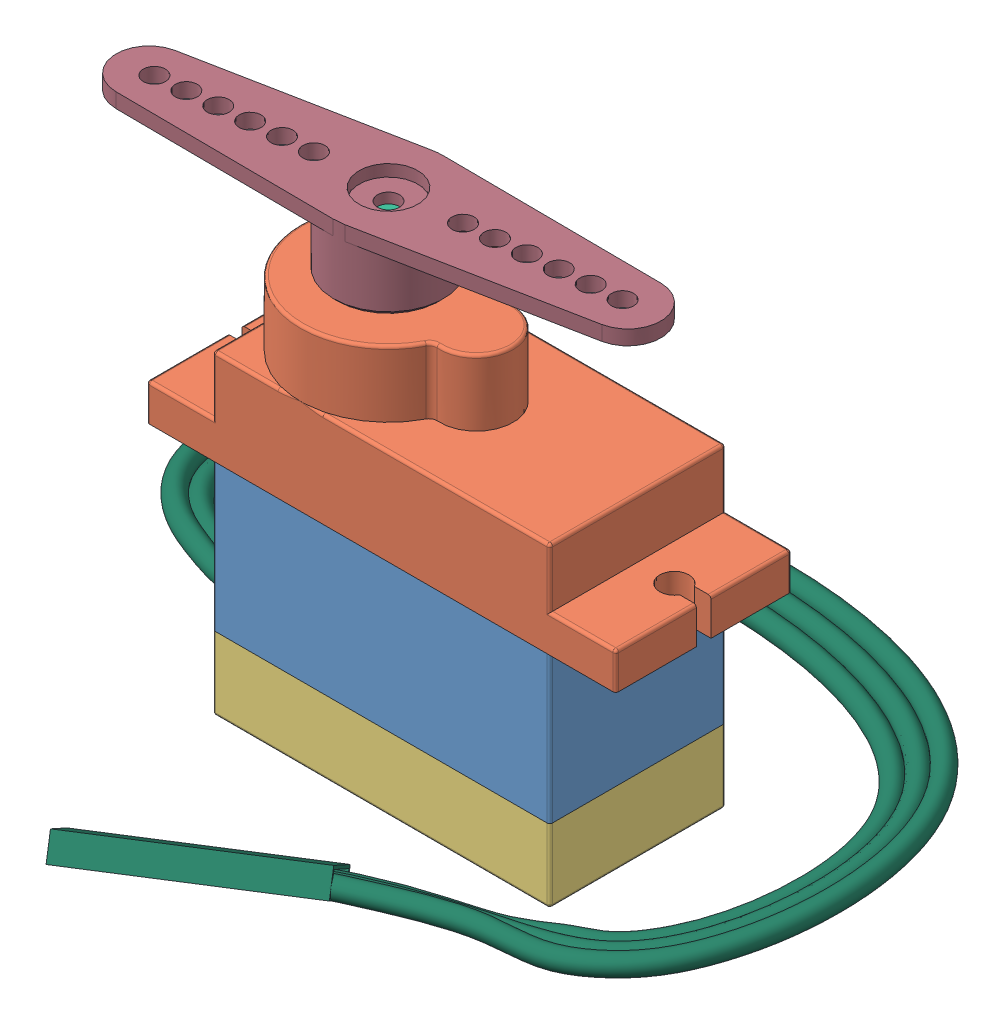
SolidWorks assembly TowPro-SG90-9g, configuration Défaut. Lengths in mm.
Overall size (48.83 32.86 44.12).
19 component instances, 15 part files, 51 mates.
Components (placement in the parent):
- Piece2-1: Piece2 [Défaut] at origin size (23 11 12)
- Piece3-1: Piece3 [Défaut] at (0 -1 0) size (32 11 12)
- Piece1-1: Piece1 [Défaut] at origin size (23 5 12)
- Gear02-1: Gear02 [Défaut] at (12.13 15.3 6) x (0 1 0) z (0.72317 0 0.69067) size (2.67 10.24 10.25)
- Gear01-1: Gear01 [Défaut] at (18.225 15 6) x (0 1 0) z (-0.948587 0 -0.316515) size (2 2.87 3)
- Gear04-1: Gear04 [Défaut] at (6 25 6) x (0 -1 0) z (0.996577 0 -0.082668) size (6.6 10.24 10.25)
- Gear02-2: Gear02 [Défaut] at (6 16.7 6) x (0 1 0) z (-0.746148 0 -0.66578) size (2.67 10.24 10.25)
- Gear03-1: Gear03 [Défaut] at (12.13 18.05 6) x (0 1 0) z (-0.892089 0 0.45186) size (6.94 10.24 10.25)
- AXE01-1: AXE01 [Défaut] at (12.13 25.5 6) x (1 0 0) z (0 -1 0) size (0.8 0.8 11)
- Pot1-1: Pot1 [Défaut] at (6 12 6) x (0 0 -1) z (0 1 0) size (10 10.16 4.72)
- Pot2-1: Pot2 [Défaut] at (6 12.0113 6) x (0.156026 0 -0.987753) z (0 1 0) size (9.16 8.4 14.53)
- Motor1-1: Motor1 [Default] at (18.225 9.2 6) x (0 0 -1) z (0 1 0) size (10.1 8.78 13.8)
- Motor2-1: Motor2 [Default] at (18.225 9.15 6) x (-0.963319 0 0.26836) z (0 1 0) size (6.5 6.42 15.75)
- A2-1: A2 [Default] at (6 31.1332 6) x (0.092609 0 0.995703) z (0 -1 0) size (7.5 34.5 5)
- Vis-1: Vis [Défaut] at (21.75 0 10.75) x (-0.99793 0 -0.064304) z (0 1 0) size (2 2 19.91)
- Vis-2: Vis [Défaut] at (1.25 0 10.75) x (1 0 0) z (0 1 0) size (2 2 19.91)
- Vis-3: Vis [Défaut] at (21.75 0 1.25) x (1 0 0) z (0 1 0) size (2 2 19.91)
- Vis-4: Vis [Défaut] at (1.25 0 1.25) x (1 0 0) z (0 1 0) size (2 2 19.91)
- W3.0-1: W3.0 [Défaut] at (0 -0.0833 0) size (48.83 7.25 44.12)
Mates (geometry in assembly coordinates):
- Coïncidente2: coincident aligned: plane of Piece2-1 through (0 0 12) normal (-1 0 0); plane of Piece3-1 through (0 17.5 12) normal (-1 0 0)
- Coïncidente3: coincident anti-aligned: plane of Piece2-1 through (-7.4113 15 12) normal (0 1 0); plane of Piece3-1 through (0 15 12) normal (0 -1 0)
- Coïncidente5: coincident anti-aligned: plane of Piece2-1 through (-7.4113 5 12) normal (0 -1 0); plane of Piece1-1 through (-7.4113 5 12) normal (0 1 0)
- Coïncidente6: coincident aligned: plane of Piece2-1 through (0 0 12) normal (-1 0 0); plane of Piece1-1 through (0 0 12) normal (-1 0 0)
- Coïncidente10: coincident anti-aligned: plane of Piece2-1 through (12.13 15.3 6) normal (0 1 0); plane of Gear02-1 through (12.13 15.3 6) normal (0 -1 0)
- Coaxiale3: concentric anti-aligned: cylinder of Piece2-1 through (12.13 14.5 6) axis (0 1 0) radius 0.4; cylinder of Gear02-1 through (12.13 15.3 6) axis (0 -1 0) radius 0.4
- Coïncidente11: coincident anti-aligned: plane of Piece2-1 through (-7.4113 15 12) normal (0 1 0); plane of Gear01-1 through (18.8118 15 5.9758) normal (0 -1 0)
- Coaxiale4: concentric anti-aligned: cylinder of Piece2-1 through (18.225 5 6) axis (0 1 0) radius 1.55; cylinder of Gear01-1 through (18.225 17 6) axis (0 -1 0) radius 0.5
- Contr.Engrenages1: gear = 39 : 10 mm: circle of Gear01-1; circle of Gear02-1
- Coïncidente12: coincident anti-aligned: plane of Piece3-1 through (6 24 6) normal (0 -1 0); plane of Gear04-1 through (6 24 6) normal (0 1 0)
- Coaxiale5: concentric anti-aligned: cylinder of Piece3-1 through (6 5.2 6) axis (0 1 0) radius 2.5; cylinder of Gear04-1 through (6 28.0001 6) axis (0 -1 0) radius 2.5
- Coaxiale6: concentric aligned: cylinder of Gear04-1 through (6 28.0001 6) axis (0 -1 0) radius 2.5; cylinder of Gear02-2 through (6 16.7 6) axis (0 -1 0) radius 0.4
- Distance1: distance = 0.4 mm anti-aligned: plane of Gear02-2 through (6 16.7 6) normal (0 -1 0); plane of Gear02-1 through (8.5903 16.3 9.7062) normal (0 1 0)
- Contr.Engrenages2: gear = 39 : 10 mm: circle of Gear02-1; circle of Gear02-2
- Coaxiale7: concentric aligned: cylinder of Gear02-1 through (12.13 15.3 6) axis (0 -1 0) radius 0.4; cylinder of Gear03-1 through (12.13 18.05 6) axis (0 -1 0) radius 0.4
- Distance2: distance = 0.35 mm anti-aligned: plane of Gear03-1 through (12.13 18.05 6) normal (0 -1 0); plane of Gear02-2 through (9.4121 17.7 2.176) normal (0 1 0)
- Contr.Engrenages3: gear = 10 : 39 mm: circle of Gear03-1; circle of Gear02-2
- Contr.Engrenages4: gear = 39 : 10 mm: circle of Gear03-1; circle of Gear04-1
- Coaxiale8: concentric anti-aligned: cylinder of Piece3-1 through (12.13 25.5 6) axis (0 -1 0) radius 0.4; cylinder of AXE01-1 through (12.13 14.5 6) axis (0 1 0) radius 0.4
- Coïncidente13: coincident anti-aligned: plane of Piece3-1 through (12.13 25.5 6) normal (0 -1 0); plane of AXE01-1 through (12.13 25.5 6) normal (0 1 0)
- Coaxiale9: concentric anti-aligned: cylinder of Piece2-1 through (6 5 6) axis (0 1 0) radius 5; cylinder of Pot1-1 through (6 15 6) axis (0 -1 0) radius 5
- Coïncidente14: coincident aligned: plane of Piece2-1 through (-7.4113 15 12) normal (0 1 0); plane of Pot1-1 through (6 15 6) normal (0 1 0)
- Coaxiale10: concentric anti-aligned: cylinder of Pot1-1 through (6 15 6) axis (0 -1 0) radius 4.75; cylinder of Pot2-1 through (6 19.6836 6) axis (0 1 0) radius 0.5
- Coïncidente15: coincident anti-aligned: plane of Pot1-1 through (6.8085 11.35 5) normal (0 -1 0); plane of Pot2-1 through (6.4939 11.35 6.078) normal (0 1 0)
- Verrouiller1: lock: unknown of Gear04-1; unknown of Pot2-1
- Parallèle1: parallel aligned: plane of Piece2-1 through (1 4 1) normal (1 0 0); plane of Pot1-1 through (7 11 10.899) normal (1 0 0)
- Coïncidente16: coincident anti-aligned: plane of Piece2-1 through (22 4 1) normal (-1 0 0); plane of Motor1-1 through (22 4.5 9.3166) normal (1 0 0)
- Coaxiale11: concentric anti-aligned: cylinder of Piece2-1 through (18.225 5 6) axis (0 1 0) radius 1.55; cylinder of Motor1-1 through (18.225 14.85 6) axis (0 -1 0) radius 1.5375
- Coïncidente17: coincident anti-aligned: plane of Piece2-1 through (0 14 0) normal (0 -1 0); plane of Motor1-1 through (18.225 14 6) normal (0 1 0)
- Coaxiale12: concentric anti-aligned: cylinder of Motor1-1 through (18.225 13.7 6) axis (0 1 0) radius 0.55; cylinder of Motor2-1 through (18.225 18.65 6) axis (0 -1 0) radius 0.5
- Coïncidente18: coincident anti-aligned: plane of Motor1-1 through (18.225 2.95 5.5) normal (0 1 0); plane of Motor2-1 through (18.225 2.95 6) normal (0 -1 0)
- Verrouiller2: lock: unknown of Gear01-1; unknown of Motor2-1
- Coaxiale13: concentric anti-aligned: cylinder of Gear04-1 through (6 28.0001 6) axis (0 -1 0) radius 2.5; cylinder of A2-1 through (6 30.1332 6) axis (0 1 0) radius 3.75
- Verrouiller3: lock: unknown of Gear04-1; unknown of A2-1
- Coïncidente19: coincident aligned: plane of Piece2-1 through (0 0 0) normal (0 0 -1); plane of Piece3-1 through (0 -1 0) normal (0 0 -1)
- Coïncidente20: coincident aligned: plane of Piece2-1 through (0 0 0) normal (0 0 -1); plane of Piece1-1 through (0 0 0) normal (0 0 -1)
- Coaxiale14: concentric aligned: cylinder of Piece1-1 through (21.75 3.5 10.75) axis (0 -1 0) radius 0.6; cylinder of Vis-1 through (21.75 19.9 10.75) axis (0 -1 0) radius 0.5
- Coïncidente21: coincident anti-aligned: plane of Piece1-1 through (21.75 0.9 10.75) normal (0 -1 0); plane of Vis-1 through (21.75 0.9 10.75) normal (0 1 0)
- Coaxiale15: concentric aligned: cylinder of Piece1-1 through (1.25 3.5 1.25) axis (0 -1 0) radius 0.6; cylinder of Vis-4 through (1.25 19.9 1.25) axis (0 -1 0) radius 0.5
- Coaxiale16: concentric aligned: cylinder of Piece1-1 through (1.25 3.5 10.75) axis (0 -1 0) radius 0.6; cylinder of Vis-2 through (1.25 19.9 10.75) axis (0 -1 0) radius 0.5
- Coaxiale17: concentric aligned: cylinder of Piece1-1 through (21.75 3.5 1.25) axis (0 -1 0) radius 0.6; cylinder of Vis-3 through (21.75 19.9 1.25) axis (0 -1 0) radius 0.5
- Coïncidente22: coincident anti-aligned: plane of Piece1-1 through (21.75 0.9 1.25) normal (0 -1 0); plane of Vis-3 through (21.75 0.9 1.25) normal (0 1 0)
- Coïncidente23: coincident anti-aligned: plane of Piece1-1 through (1.25 0.9 10.75) normal (0 -1 0); plane of Vis-2 through (1.25 0.9 10.75) normal (0 1 0)
- Coïncidente24: coincident anti-aligned: plane of Piece1-1 through (1.25 0.9 1.25) normal (0 -1 0); plane of Vis-4 through (1.25 0.9 1.25) normal (0 1 0)
- Verrouiller4: lock: unknown of Gear01-1; unknown of Motor2-1
- Coïncidente25: coincident aligned: plane of Piece1-1 through (1 11 1) normal (1 0 0); plane of W3.0-1 through (1 4.1667 6) normal (1 0 0)
- Tangent1: tangent: plane of Piece1-1 through (3.5 3.5 4) normal (0 1 0); circle of W3.0-1
- Coïncidente27: coincident: line of Piece1-1 through (1 5 4) axis (0 -1 0); moEndPointRef_w of W3.0-1
- Coincident1: coincident aligned: plane of ? through (0 0 0) normal (0 0 1)
- Coincident2: coincident aligned: plane of ? through (0 0 0) normal (0 1 0)
- Coincident3: coincident aligned: plane of ? through (0 0 0) normal (1 0 0)
